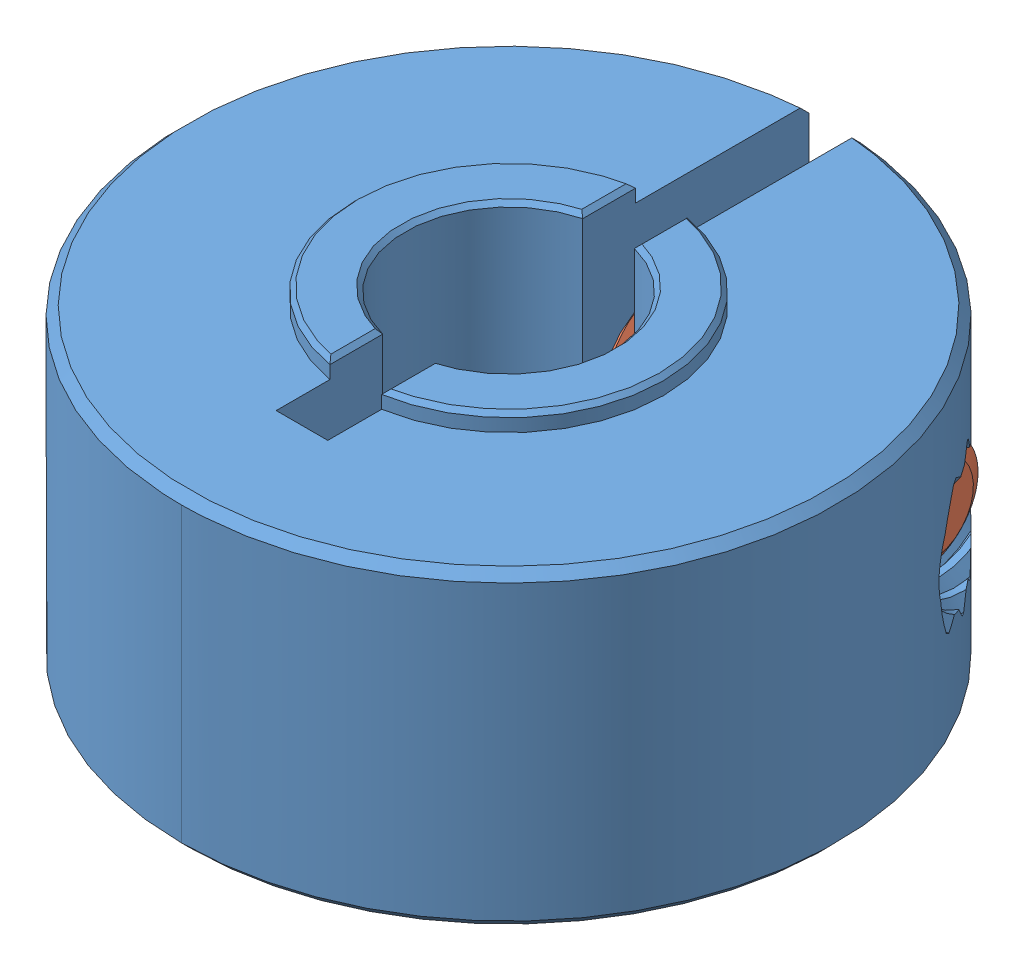
SolidWorks assembly 6mm ID collar 2910-0919-0006, configuration Default. Lengths in mm.
Overall size (19 9.89 19.83).
2 component instances, 2 part files, 0 mates.
Components (placement in the parent):
- 2910-0919-0006.STEP-1: 2910-0919-0006.STEP [Default] at (-31.0565 -0.5204 16.7268) size (19 9.5 18.97)
- 2800-0004-0010_90128A207.STEP-1: 2800-0004-0010_90128A207.STEP [Default] at (-24.2865 -0.5204 11.2868) x (0 -0.807243 -0.59022) z (1 0 0) size (7 7 14.01)
